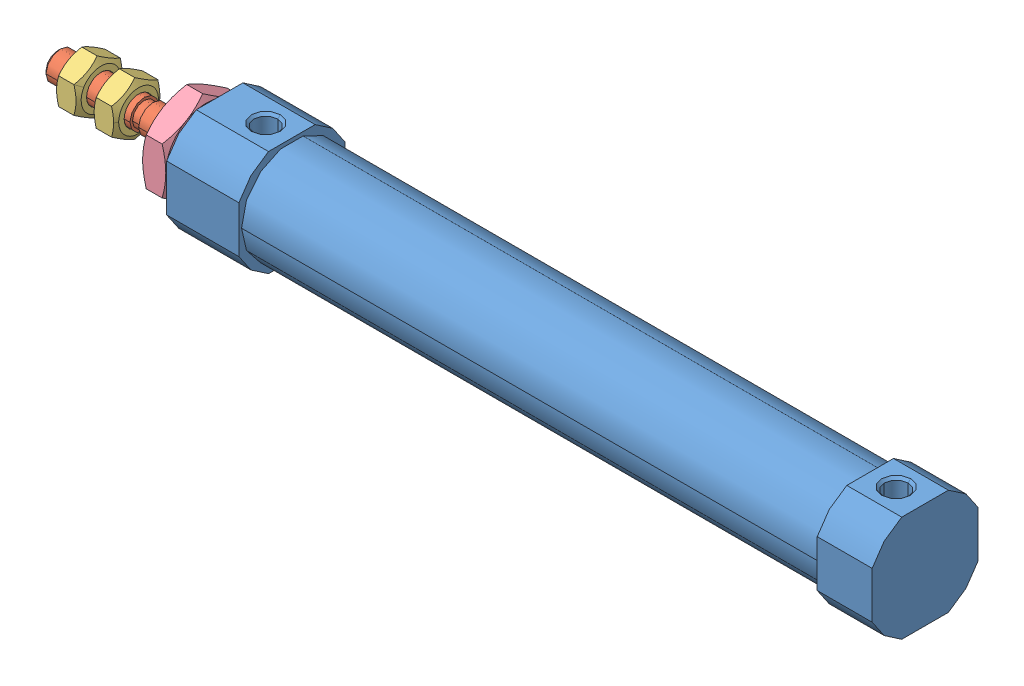
SolidWorks assembly CJ2B16_75Z_0_0_0_, configuration Default. Lengths in mm.
Overall size (150 18.3 18.3).
5 component instances, 4 part files, 0 mates.
Components (placement in the parent):
- _CJ2B16_75Z_0_0__BODY_2-1: _CJ2B16_75Z_0_0__BODY_2 [Default] at origin size (130 18.3 18.3)
- _CJ2B16_75Z_ROD_4-1: _CJ2B16_75Z_ROD_4 [Default] at (-28 0 0) size (120.5 16 16)
- _NTJ_015C_6-1: _NTJ_015C_6 [Default] at (-16 0 0) x (-1 0 0) z (0 0 1) size (4 9.25 10.62)
- _NTJ_015C_6-2: _NTJ_015C_6 [Default] at (-22.5 0 0) size (4 9.25 10.62)
- _SNJ_016C_9-1: _SNJ_016C_9 [Default] at (-4.3 0 0) size (4.01 16.17 18.05)
